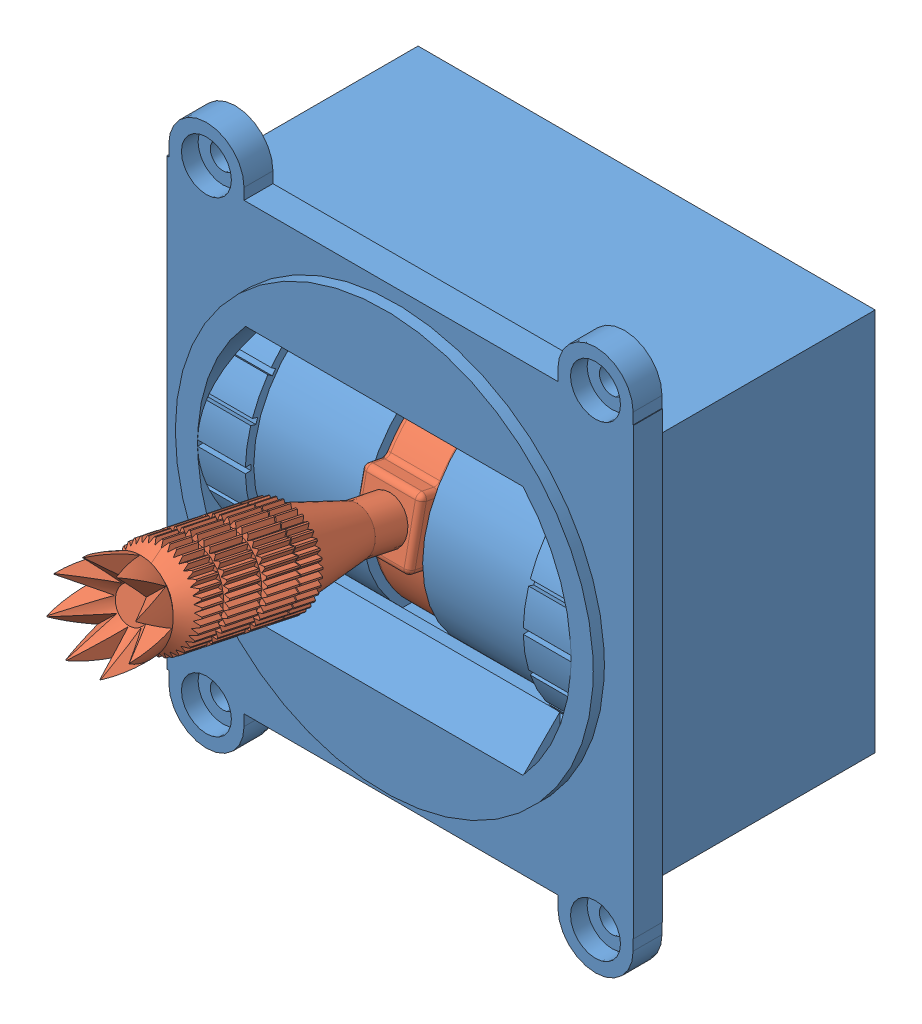
SolidWorks assembly 摇杆手柄, configuration 默认. Lengths in mm.
Overall size (42 48.77 51.99).
2 component instances, 2 part files, 2 mates.
Components (placement in the parent):
- 摇杆底座-1: 摇杆底座 [默认] at (3.7212 -6.9245 56.97) size (42 48.77 23.6)
- 摇杆手柄-1: 摇杆手柄 [默认] at (13.0483 115.832 37.8707) x (0 0.978849 -0.204586) z (1 0 0) size (20 48.5 9.07)
Mates (geometry in assembly coordinates):
- 同心1: concentric: cylinder of 摇杆底座-1 through (16.2212 -6.9245 49.2251) axis (-1 0 0) radius 10.5955; cylinder of 摇杆手柄-1 through (1.0212 -6.9245 49.2251) axis (1 0 0) radius 10
- 宽度1: width: plane of 摇杆手柄-1 through (1.0212 112.9678 24.1669) normal (-1 0 0); plane of 摇杆手柄-1 through (6.4212 112.9678 24.1669) normal (1 0 0); plane of 摇杆底座-1 through (-8.7788 -6.9245 56.97) normal (-1 0 0); plane of 摇杆底座-1 through (16.2212 -6.9245 56.97) normal (1 0 0)
